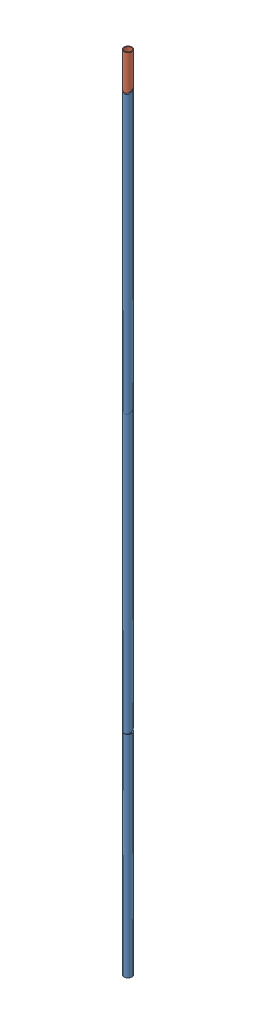
SolidWorks assembly Assem1, configuration Default. Lengths in mm.
Overall size (355.76 1255.2 415.63).
4 component instances, 2 part files, 4 mates.
Components (placement in the parent):
- RakedSensorMastTubes-1: RakedSensorMastTubes [Straight] at (0.1399 0 0) size (12.7 330.2 12.7)
- RakedSensorMastTubes-2: RakedSensorMastTubes [Angled] at (-8.1089 433.8773 19.5266) x (0.70548 0.294384 -0.644698) z (-0.66866 0.577997 -0.467774) size (141.34 330.23 266.91)
- RakedSensorMastTubes-3: RakedSensorMastTubes [Angled] at (-8.1089 0.0256 19.5266) x (0.70548 0.294384 -0.644698) z (-0.66866 0.577997 -0.467774) size (141.34 330.23 266.91)
- CutTemplate-1: CutTemplate [Default] at (0.1399 826.5735 0) x (-0.932225 0 0.36188) z (0 1 0) size (12.7 12.7 101.6)
Mates (geometry in assembly coordinates):
- Concentric1: concentric aligned: cylinder of RakedSensorMastTubes-2 through (0.1399 418.7168 0) axis (0 1 0) radius 6.35; cylinder of RakedSensorMastTubes-3 through (0.1399 -15.1348 0) axis (0 1 0) radius 6.35
- Concentric3: concentric aligned: cylinder of RakedSensorMastTubes-1 through (0.1399 -327.025 0) axis (0 1 0) radius 6.35; cylinder of RakedSensorMastTubes-2 through (0.1399 418.7168 0) axis (0 1 0) radius 6.35
- Coincident2: coincident anti-aligned: plane of RakedSensorMastTubes-2 through (-8.8548 431.4608 17.6069) normal (-0.234929 -0.76109 -0.604608); plane of RakedSensorMastTubes-3 through (-3.2332 450.6086 -8.6809) normal (0.234929 0.76109 0.604608)
- Concentric4: concentric anti-aligned: cylinder of RakedSensorMastTubes-2 through (0.1399 418.7168 0) axis (0 1 0) radius 6.35; cylinder of CutTemplate-1 through (0.1399 928.1735 0) axis (0 -1 0) radius 6.35
